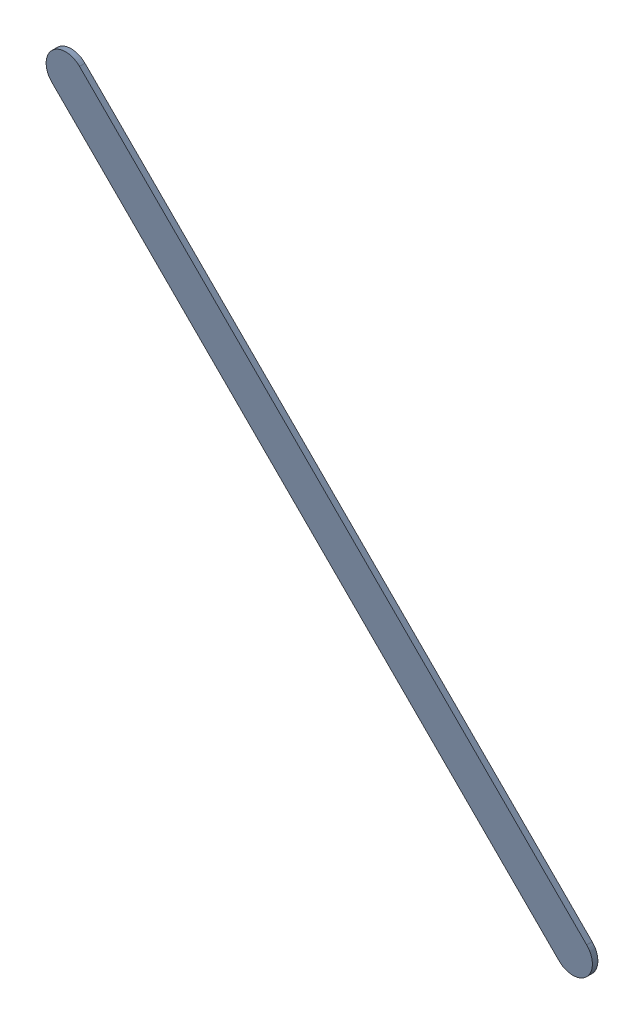
SolidWorks assembly Track (11.2mm,10.1mm)(14.5mm,6.8mm) on Top Layer, configuration Predeterminado. Lengths in mm.
Overall size (3.55 3.55 0.04).
2 component instances, 1 part files, 0 mates.
Components (placement in the parent):
- Track (11.2mm,10.1mm)(14.5mm,6.8mm) on Top Layer-1-1: Track (11.2mm,10.1mm)(14.5mm,6.8mm) on Top Layer-1 [Predeterminado] at (-68.317 -44.187 -0.0457) size (3.55 3.55 0.04)
  - Track (11.2mm,10.1mm)(14.5mm,6.8mm) on Top Layer-Part-1-1: Track (11.2mm,10.1mm)(14.5mm,6.8mm) on Top Layer-Part-1 [Predeterminado] at origin size (3.55 3.55 0.04)
